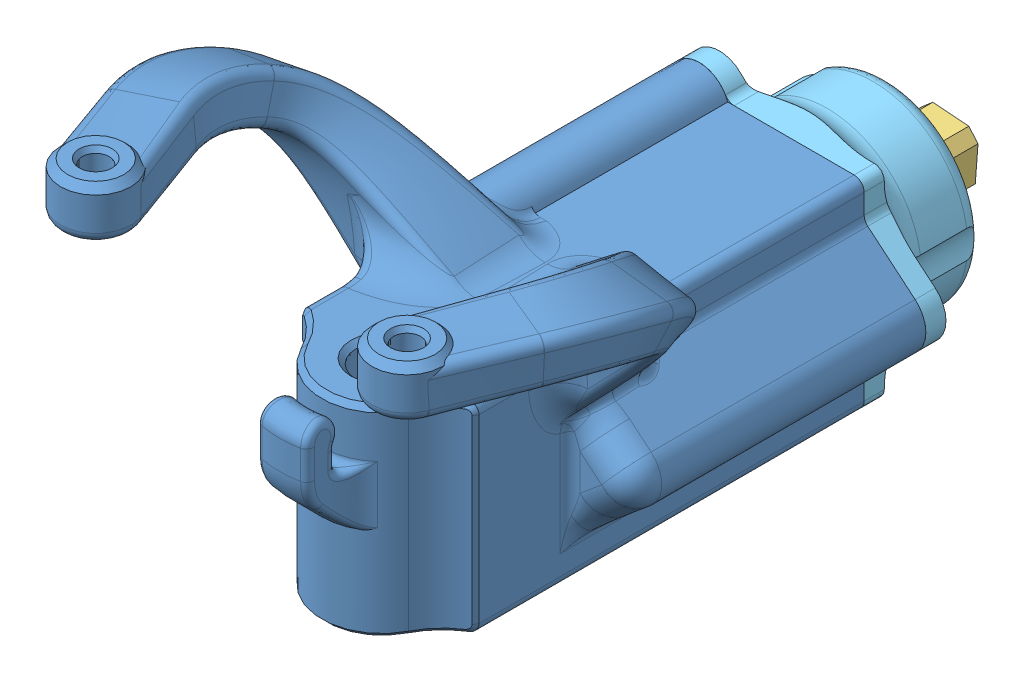
SolidWorks assembly Assem_new, configuration Default. Lengths in mm.
Overall size (48.17 38.87 74.84).
5 component instances, 5 part files, 15 mates.
Components (placement in the parent):
- SD-209 Knuckle-1: SD-209 Knuckle [Default] at (7.0379 25.8547 67.2046) size (48.17 38.87 57.57)
- newmotor-1: newmotor [Default] at (1.8879 19.8547 40.2046) x (-1 0 0) z (0 1 0) size (10 39 12)
- spline adapter-1: spline adapter [Default] at (6.8879 25.8547 26.9446) x (-0.997189 0.074926 0) z (-0.074926 -0.997189 0) size (9.57 19.74 9.57)
- WW bearing-1: WW bearing [Default] at (6.8879 25.8547 18.3246) size (16 16 4.95)
- SD-204 Wheel Bearing Retainer-1: SD-204 Wheel Bearing Retainer [Default] at (7.0379 25.8547 27.9246) x (-1 0 0) z (0 0 -1) size (25.54 24 11.1)
Mates (geometry in assembly coordinates):
- Coincident3: coincident: plane of SD-209 Knuckle-1 through (7.0379 25.8547 40.2046) normal (0 0 -1); plane of newmotor-1 through (1.8879 19.8547 40.2046) normal (0 0 1)
- Coincident4: coincident: plane of SD-209 Knuckle-1 through (7.0379 25.8547 40.2046) normal (0 0 -1); plane of newmotor-1 through (1.8879 19.8547 40.2046) normal (0 0 1)
- Coincident5: coincident: plane of SD-209 Knuckle-1 through (7.0379 25.8547 40.2046) normal (0 0 -1); plane of newmotor-1 through (1.8879 19.8547 40.2046) normal (0 0 1)
- Coincident6: coincident: plane of SD-209 Knuckle-1 through (7.0379 19.8547 79.717) normal (0 1 0); plane of newmotor-1 through (1.8879 19.8547 55.2046) normal (0 -1 0)
- Coincident7: coincident: plane of SD-209 Knuckle-1 through (1.8879 32.1547 21.5833) normal (1 0 0); plane of newmotor-1 through (1.8879 19.8547 55.2046) normal (-1 0 0)
- Coincident8: coincident: plane of newmotor-1 through (1.8879 26.6047 30.4046) normal (0 1 0); plane of spline adapter-1 through (6.8879 27.0547 24.2046) normal (0 -1 0)
- Coincident9: coincident: plane of newmotor-1 through (6.8879 25.8547 30.4046) normal (0 0 -1); plane of spline adapter-1 through (6.8879 25.8547 30.4046) normal (0 0 1)
- Parallel1: parallel: cylinder of newmotor-1 through (6.8879 25.8547 21.2046) axis (0 0 1) radius 1.25; cylinder of spline adapter-1 through (6.8879 25.8547 24.2046) axis (0 0 1) radius 1.6
- Concentric6: concentric: circle of newmotor-1; cylinder of spline adapter-1 through (6.8879 25.8547 26.9446) axis (0 0 1) radius 1.295
- Concentric7: concentric: cylinder of spline adapter-1 through (6.8879 25.8547 26.9446) axis (0 0 1) radius 3.97; cylinder of WW bearing-1 through (6.8879 25.8547 23.2746) axis (0 0 -1) radius 4
- Coincident10: coincident: plane of spline adapter-1 through (10.8468 25.5572 23.2746) normal (0 0 -1); plane of WW bearing-1 through (6.8879 25.8547 23.2746) normal (0 0 1)
- Concentric8: concentric: cylinder of SD-209 Knuckle-1 through (-0.6621 34.8547 56.2046) axis (0 0 -1) radius 1.3; circle of SD-204 Wheel Bearing Retainer-1
- Concentric9: concentric: cylinder of SD-209 Knuckle-1 through (-0.6621 16.8547 56.2046) axis (0 0 -1) radius 1.3; cylinder of SD-204 Wheel Bearing Retainer-1 through (-0.6621 16.8547 16.8246) axis (0 0 1) radius 1.55
- Coincident11: coincident: plane of SD-209 Knuckle-1 through (7.0379 25.8547 24.1046) normal (0 0 -1); plane of SD-204 Wheel Bearing Retainer-1 through (-0.6621 34.8547 24.1046) normal (0 0 1)
- Coincident12: coincident: plane of SD-209 Knuckle-1 through (14.7379 16.8547 27.9246) normal (0 0 -1); plane of SD-204 Wheel Bearing Retainer-1 through (-0.6621 34.8547 27.9246) normal (0 0 1)
